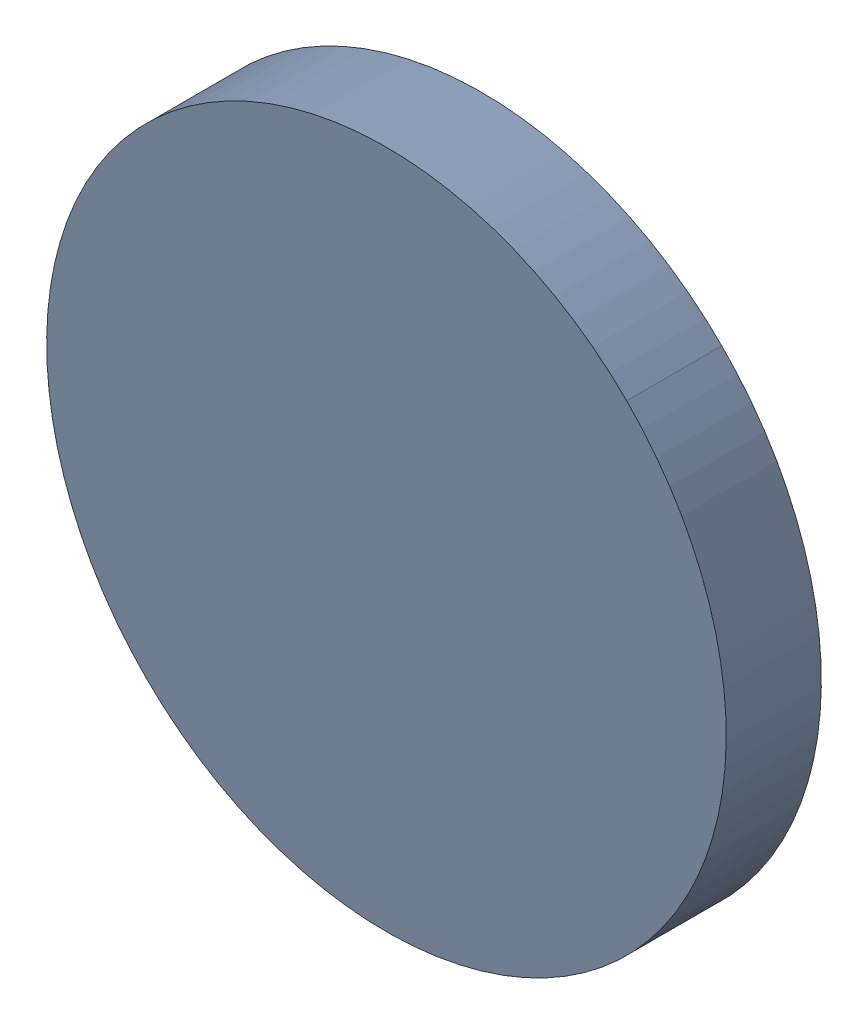
SolidWorks assembly Track (14.5mm,22.5mm)(14.5mm,22.5mm) on Top Layer, configuration Predeterminado. Lengths in mm.
Overall size (0.25 0.25 0.04).
2 component instances, 1 part files, 0 mates.
Components (placement in the parent):
- Track (14.5mm,22.5mm)(14.5mm,22.5mm) on Top Layer-1-1: Track (14.5mm,22.5mm)(14.5mm,22.5mm) on Top Layer-1 [Predeterminado] at (-68.317 -44.187 -0.0457) size (0.25 0.25 0.04)
  - Track (14.5mm,22.5mm)(14.5mm,22.5mm) on Top Layer-Part-1-1: Track (14.5mm,22.5mm)(14.5mm,22.5mm) on Top Layer-Part-1 [Predeterminado] at origin size (0.25 0.25 0.04)
